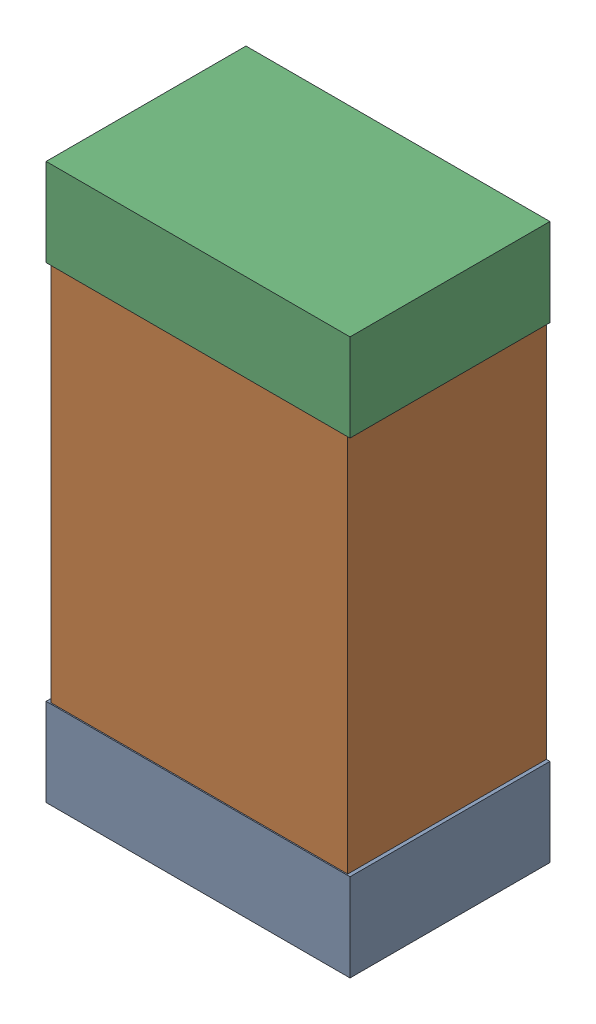
SolidWorks assembly C11Kanaloa_v2.0.0_GPIO_b, configuration Default. Lengths in mm.
Overall size (1.3 2.38 0.85).
6 component instances, 2 part files, 0 mates.
Components (placement in the parent):
- 330415056-1: 330415056 [Default] at (67.945 129.175 0) size (1.3 0.38 0.85)
  - Extruded_2-1: Extruded_2 [Default] at origin size (1.3 0.38 0.85)
- 352877008-1: 352877008 [Default] at (67.945 130.175 0) size (1.27 2.2 0.85)
  - Extruded_3-1: Extruded_3 [Default] at origin size (1.27 2.2 0.85)
- 330415056-2: 330415056 [Default] at (67.945 131.175 0) size (1.3 0.38 0.85)
  - Extruded_2-1: Extruded_2 [Default] at origin size (1.3 0.38 0.85)
